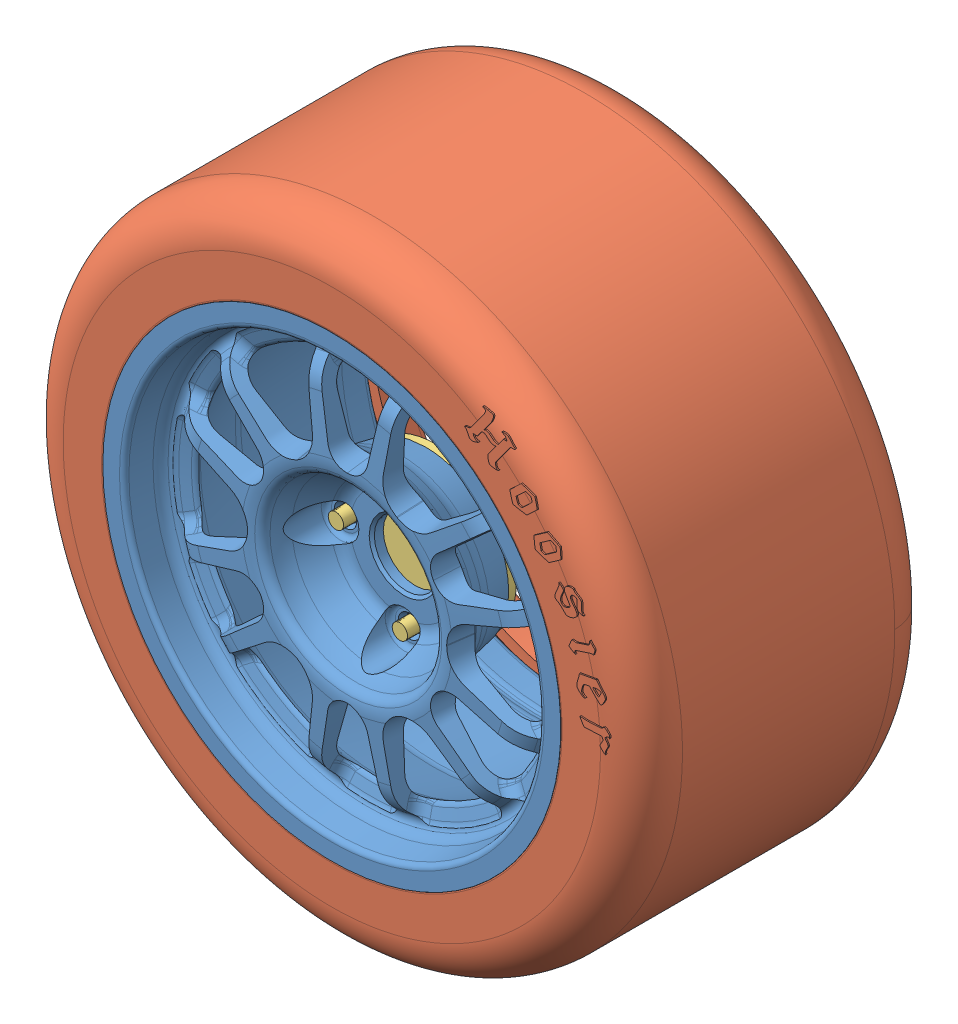
SolidWorks assembly wheel and tire- WITH HUB, configuration Default. Lengths in mm.
Overall size (484.14 484.14 231.18).
3 component instances, 3 part files, 10 mates.
Components (placement in the parent):
- OZ Al 7x13 Wheel-1: OZ Al 7x13 Wheel [Default] at (0 0 19.8) x (-1 0 0) z (0 0 1) size (359.65 359.65 190.61)
- Hoosier 20.5x7x13 R25B A2500 Tire-2: Hoosier 20.5x7x13 R25B A2500 Tire [Default] at origin size (484.14 484.14 231.18)
- HUB-PROTOTYPE-1: HUB-PROTOTYPE [Default] at (0 0 49.8) x (-1 0 0) z (0 0 -1) size (126 126 28)
Mates (geometry in assembly coordinates):
- Coincident5: coincident anti-aligned: plane of OZ Al 7x13 Wheel-1; plane of assembly through (0 0 0) normal (0 1 0)
- Parallel1: parallel aligned: plane of OZ Al 7x13 Wheel-1 through (0 0 19.8) normal (0 0 1); plane of assembly through (0 0 0) normal (0 0 1)
- Coincident7: coincident anti-aligned: plane of OZ Al 7x13 Wheel-1; plane of assembly through (0 0 0) normal (1 0 0)
- Coincident8: coincident aligned: plane of Hoosier 20.5x7x13 R25B A2500 Tire-2 through (0 0 0) normal (0 1 0); plane of assembly through (0 0 0) normal (0 1 0)
- Coincident9: coincident aligned: plane of Hoosier 20.5x7x13 R25B A2500 Tire-2 through (0 0 0) normal (1 0 0); plane of assembly through (0 0 0) normal (1 0 0)
- Coincident10: coincident aligned: plane of Hoosier 20.5x7x13 R25B A2500 Tire-2 through (0 0 0) normal (0 0 1); plane of assembly through (0 0 0) normal (0 0 1)
- Coincident12: coincident aligned: plane of OZ Al 7x13 Wheel-1 through (89.53 0 115) normal (0 0 1); plane of Hoosier 20.5x7x13 R25B A2500 Tire-2 through (212.52 -212.52 115) normal (0 0 1)
- Coincident13: coincident anti-aligned: axis of Hoosier 20.5x7x13 R25B A2500 Tire-2 through (0 0 68.243) axis (0 0 -1); axis of HUB-PROTOTYPE-1 through (0 0 33.8) axis (0 0 1)
- Coincident14: coincident aligned: axis of OZ Al 7x13 Wheel-1 through (0 -50 66.8289) axis (0 0 -1); axis of HUB-PROTOTYPE-1 through (0 -50 61.8) axis (0 0 -1)
- Coincident15: coincident anti-aligned: plane of OZ Al 7x13 Wheel-1 through (32.5 0 41.8) normal (0 0 -1); plane of HUB-PROTOTYPE-1 through (0 0 41.8) normal (0 0 1)
